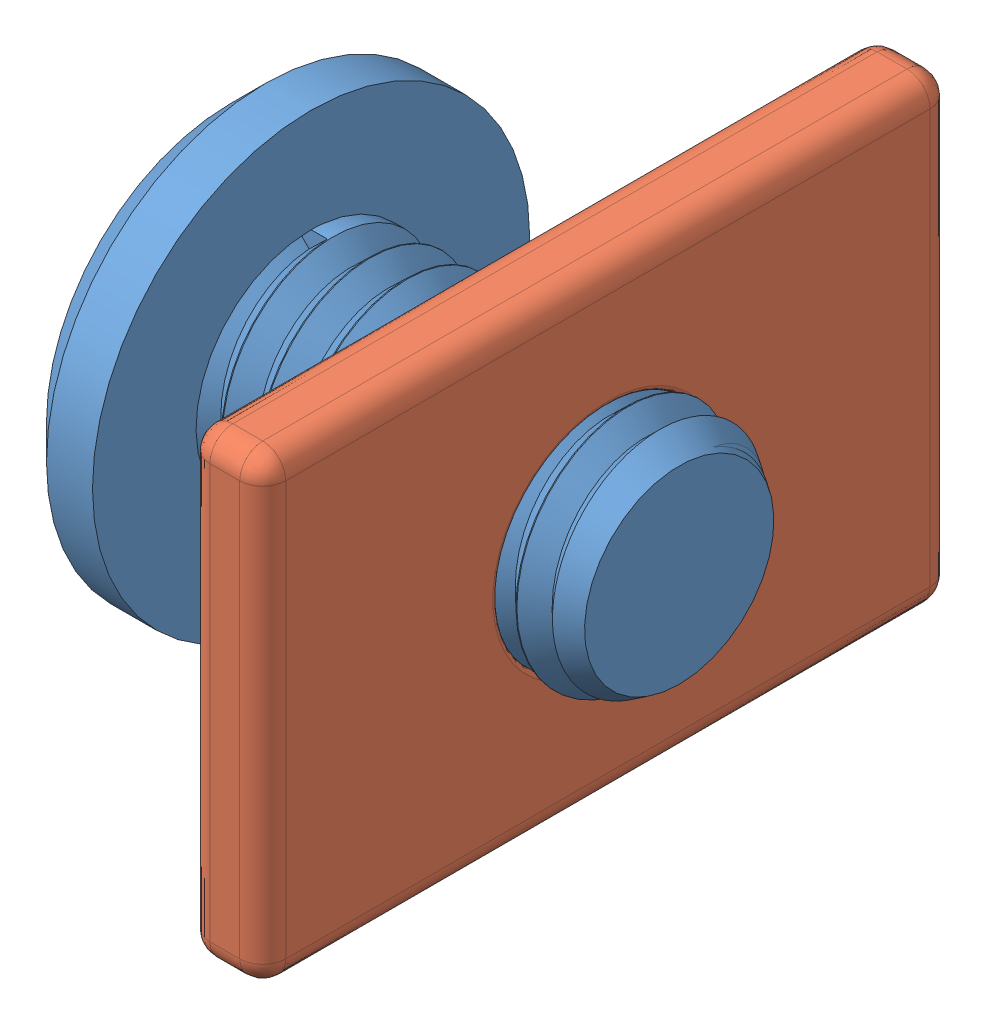
SolidWorks assembly 5mm x 8mm Bolt with Tee Nut, configuration Default. Lengths in mm.
Overall size (10.1 10 15).
2 component instances, 2 part files, 2 mates.
Components (placement in the parent):
- 5mm x 8mm Low Profile Socket Head Screw-1: 5mm x 8mm Low Profile Socket Head Screw [5mm x 8mm Low Profile] at (-34.8438 7.7195 10.4769) size (10.1 9.5 9.5)
- Tee nut-1: Tee nut [Default] at (-28.2938 2.7205 17.9769) x (0 0 -1) z (1 0 0) size (15 10 3.3)
Mates (geometry in assembly coordinates):
- Concentric1: concentric anti-aligned: cylinder of 5mm x 8mm Low Profile Socket Head Screw-1 through (-34.8438 7.7195 10.4769) axis (-1 0 0) radius 4.75; cylinder of Tee nut-1 through (-29.9438 7.7195 10.4769) axis (1 0 0) radius 2.4
- Distance1: distance = 4.8 mm anti-aligned: plane of Tee nut-1 through (-28.2938 2.7205 17.9769) normal (-1 0 0); plane of 5mm x 8mm Low Profile Socket Head Screw-1 through (-33.0938 10.2195 10.4769) normal (1 0 0)
